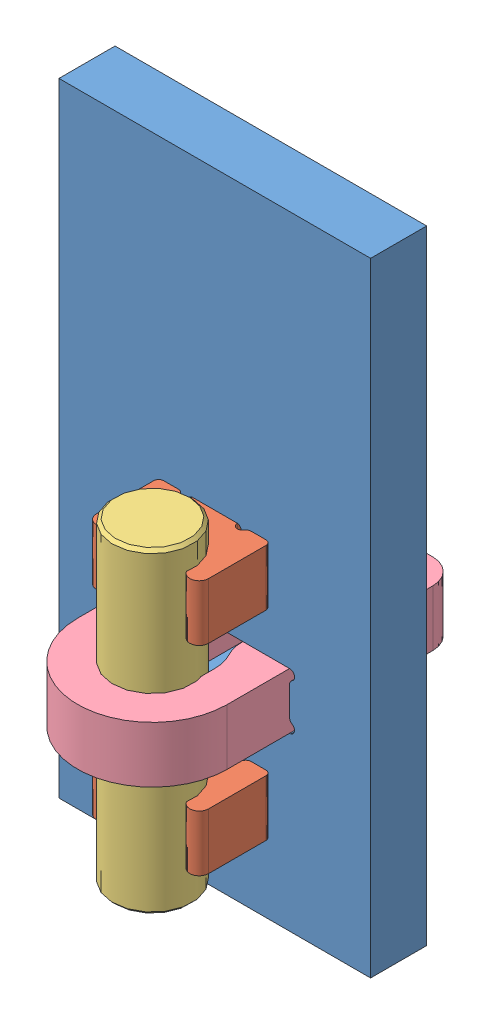
SolidWorks assembly clamp-with-wedge, configuration Default. Lengths in mm.
Overall size (25 51.71 24.5).
6 component instances, 5 part files, 10 mates.
Components (placement in the parent):
- clamp-web-1: clamp-web [Default] at (-27.2145 -35.2209 12.4586) size (25 50 4.5)
- clamp-base-1: clamp-base [Default] at (-14.7145 -29.4709 21.9586) x (-1 0 0) z (0 0 -1) size (9 4.5 9.75)
- clamp-base-2: clamp-base [Default] at (-14.7145 -13.4709 21.9586) x (-1 0 0) z (0 0 -1) size (9 4.5 9.75)
- generic_dowel_pin-1: generic_dowel_pin [0.25 x 1] at (-14.7145 -19.7042 21.9586) x (0 -1 0) z (0.312859 0 0.9498) size (25.4 6.35 6.35)
- clamp-tensioner-1: clamp-tensioner [Default] at (-14.7145 -21.4709 21.9586) x (-1 0 0) z (0 0 -1) size (12 4.5 24.5)
- wedge-1: wedge [Default] at (-16.9645 -11.9304 12.4586) x (0 -1 0) z (1 0 0) size (25 5.81 4.5)
Mates (geometry in assembly coordinates):
- Coincident1: coincident anti-aligned: plane of clamp-web-1 through (-27.2145 -35.2209 16.9586) normal (0 0 1); plane of clamp-base-1 through (-17.6161 -24.9709 16.9586) normal (0 0 -1)
- Coincident2: coincident anti-aligned: plane of clamp-web-1 through (-14.7145 -29.4709 12.4576) normal (0 1 0); plane of clamp-base-1 through (-10.9645 -29.4709 21.9586) normal (0 -1 0)
- Coincident3: coincident: plane of clamp-web-1 through (-12.9645 -26.0638 12.4576) normal (-1 0 0); line of clamp-base-1 through (-12.9645 -24.9709 13.3516) axis (0 -1 0)
- Concentric1: concentric anti-aligned: cylinder of clamp-base-1 through (-14.7145 -24.9709 21.9586) axis (0 -1 0) radius 3; cylinder of generic_dowel_pin-1 through (-14.7145 -32.4042 21.9586) axis (0 1 0) radius 3.175
- Coincident4: coincident anti-aligned: plane of clamp-web-1 through (-20.7145 -21.4709 12.4576) normal (0 1 0); plane of clamp-tensioner-1 through (-14.7145 -21.4709 21.9586) normal (0 -1 0)
- Coincident5: coincident anti-aligned: plane of clamp-web-1 through (-8.7145 -18.0638 12.4576) normal (-1 0 0); plane of clamp-tensioner-1 through (-8.7145 -16.9709 16.9586) normal (1 0 0)
- Concentric2: concentric anti-aligned: cylinder of generic_dowel_pin-1 through (-14.7145 -32.4042 21.9586) axis (0 1 0) radius 3.175; cylinder of clamp-tensioner-1 through (-14.7145 -16.9709 21.9586) axis (0 -1 0) radius 3
- Coincident6: coincident anti-aligned: plane of clamp-web-1 through (-27.2145 -35.2209 12.4586) normal (0 0 -1); plane of wedge-1 through (-12.4645 -11.9304 12.4586) normal (0 0 1)
- Coincident7: coincident anti-aligned: plane of clamp-tensioner-1 through (-16.9645 -16.9709 16.9586) normal (1 0 0); plane of wedge-1 through (-16.9645 -11.9304 12.4586) normal (-1 0 0)
- Coincident8: coincident: line of clamp-tensioner-1 through (-12.4645 -21.4709 7.4586) axis (-1 0 0); plane of wedge-1 through (-12.4645 -11.9304 7.9586) normal (0 0.052336 -0.99863)
